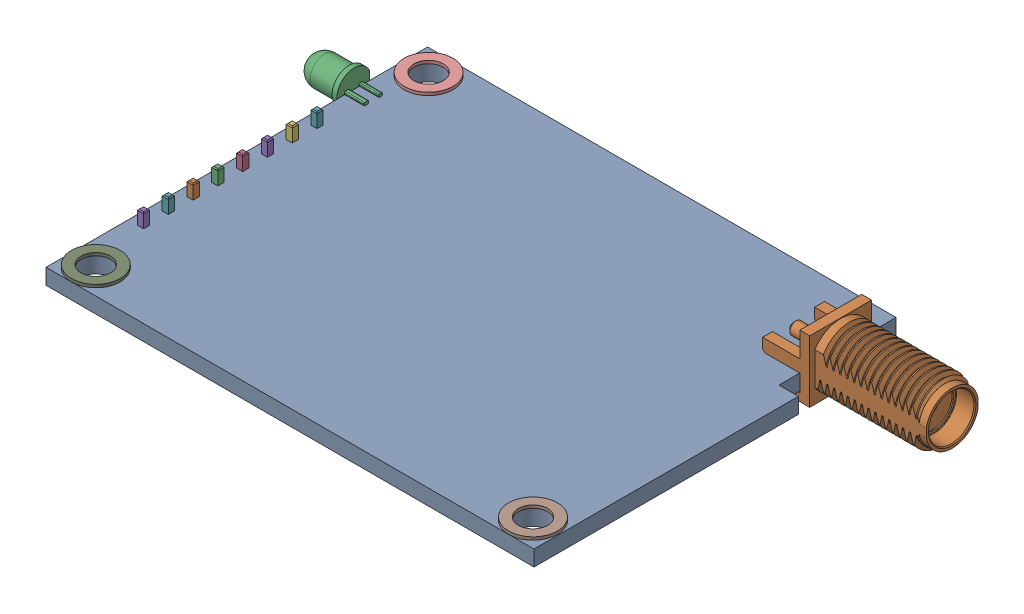
SolidWorks assembly DRF7020D27, configuration Default. Lengths in mm.
Overall size (64.95 13.39 39.1).
21 component instances, 6 part files, 9 mates.
Components (placement in the parent):
- DRF7020-1: DRF7020 [Default] at (10.1918 11.3625 20.3239) size (50 1.6 39.1)
- 73251-2123-1: 73251-2123 [Default] at (45.6378 13.5975 7.4694) x (0 0 1) z (0 -1 0) size (6.36 16.26 6.48)
- LED 3mm RED-1: LED 3mm RED [Standard] at (-14.8082 13.1125 8.3079) x (0 0 -1) z (0 1 0) size (3.33 6.5 3.5)
- Male Header Pin Config-1: Male Header Pin Config [11 pin] at (-13.5382 11.3625 31.1517) x (0 0 -1) z (-1 0 0) size (20.32 10.95 2.54)
  - Spacer-1: Spacer [Default] at origin size (2.54 2.4 2.54)
  - Male Header Pin-1: Male Header Pin [Default] at (0 -3.03 0) x (0 0 1) z (-1 0 0) size (0.63 10.95 0.63)
  - Spacer-2: Spacer [Default] at (2.54 0 0) size (2.54 2.4 2.54)
  - Male Header Pin-2: Male Header Pin [Default] at (2.54 -3.03 0) x (0 0 1) z (-1 0 0) size (0.63 10.95 0.63)
  - Spacer-3: Spacer [Default] at (5.08 0 0) size (2.54 2.4 2.54)
  - Spacer-4: Spacer [Default] at (7.62 0 0) size (2.54 2.4 2.54)
  - Spacer-5: Spacer [Default] at (10.16 0 0) size (2.54 2.4 2.54)
  - Spacer-6: Spacer [Default] at (12.7 0 0) size (2.54 2.4 2.54)
  - Spacer-7: Spacer [Default] at (15.24 0 0) size (2.54 2.4 2.54)
  - Spacer-8: Spacer [Default] at (17.78 0 0) size (2.54 2.4 2.54)
  - Male Header Pin-3: Male Header Pin [Default] at (5.08 -3.03 0) x (0 0 1) z (-1 0 0) size (0.63 10.95 0.63)
  - Male Header Pin-4: Male Header Pin [Default] at (7.62 -3.03 0) x (0 0 1) z (-1 0 0) size (0.63 10.95 0.63)
  - Male Header Pin-5: Male Header Pin [Default] at (10.16 -3.03 0) x (0 0 1) z (-1 0 0) size (0.63 10.95 0.63)
  - Male Header Pin-6: Male Header Pin [Default] at (12.7 -3.03 0) x (0 0 1) z (-1 0 0) size (0.63 10.95 0.63)
  - Male Header Pin-7: Male Header Pin [Default] at (15.24 -3.03 0) x (0 0 1) z (-1 0 0) size (0.63 10.95 0.63)
  - Male Header Pin-8: Male Header Pin [Default] at (17.78 -3.03 0) x (0 0 1) z (-1 0 0) size (0.63 10.95 0.63)
- spacer_-2: spacer_ [Default] at (10.1918 12.9625 20.3239) size (49.8 0.3 39.1)
Mates (geometry in assembly coordinates):
- Coincident1: coincident anti-aligned: plane of 73251-2123-1 through (29.3818 12.9625 12.9001) normal (0 -1 0); plane of DRF7020-1 through (10.1918 12.9625 20.3239) normal (0 1 0)
- Coincident2: coincident anti-aligned: plane of DRF7020-1 through (33.1918 12.9625 0.7739) normal (1 0 0); plane of 73251-2123-1 through (33.1918 13.5975 7.4694) normal (-1 0 0)
- Coincident4: coincident anti-aligned: plane of DRF7020-1 through (10.1918 12.9625 20.3239) normal (0 1 0); plane of LED 3mm RED-1 through (-12.8082 12.9625 9.2079) normal (0 -1 0)
- Coincident5: coincident anti-aligned: plane of DRF7020-1 through (-14.8082 12.9625 39.8739) normal (-1 0 0); plane of LED 3mm RED-1 through (-14.8082 13.1125 8.3079) normal (1 0 0)
- Coincident6: coincident anti-aligned: plane of DRF7020-1 through (10.1918 11.3625 20.3239) normal (0 -1 0); plane of Male Header Pin Config-1/Spacer-6 through (-13.5382 11.3625 18.4517) normal (0 1 0)
- Coincident7: coincident aligned: plane of DRF7020-1 through (-14.8082 12.9625 39.8739) normal (-1 0 0); plane of Male Header Pin Config-1/Spacer-1 through (-14.8082 8.9625 32.4217) normal (-1 0 0)
- Coincident9: coincident aligned: circle of DRF7020-1; circle of spacer_-2
- Coincident10: coincident aligned: circle of DRF7020-1; circle of spacer_-2
- Distance2: distance = 3.525 mm: line of 73251-2123-1 through (29.6358 11.1845 4.2944) axis (1 0 0); line of DRF7020-1 through (33.1918 11.3625 0.7739) axis (-1 0 0)
